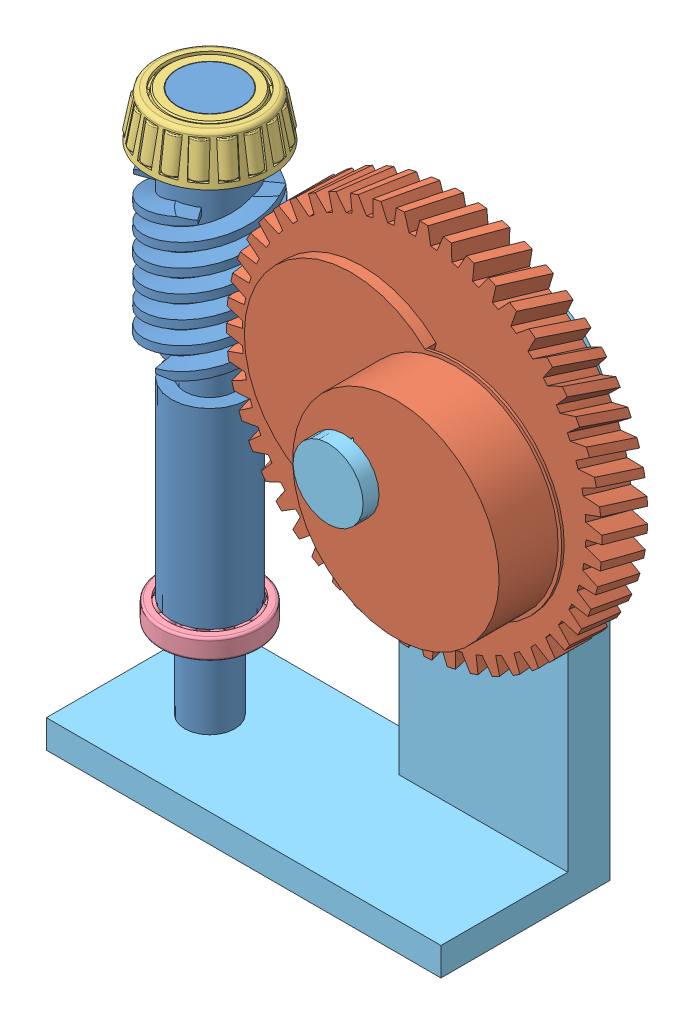
SolidWorks assembly gear Ass, configuration Default. Lengths in mm.
Overall size (190.62 222.52 70).
5 component instances, 5 part files, 9 mates.
Components (placement in the parent):
- worm gear-1: worm gear [Default] at (-73.4139 -3.3795 118.0562) x (0 0 1) z (-1 0 0) size (38.77 202.56 38.77)
- helical gear-1: helical gear [Default] at (8.555 135.9465 111.2804) x (0.238118 0.971236 0) z (0 0 1) size (133.38 133.38 45.09)
- Cone Bearing-1: Cone Bearing [Default] at (-73.4139 182.2945 118.0562) x (0 1 0) z (0 0 1) size (17.14 43.76 43.71)
- Ball Bearing-1: Ball Bearing [AFBMA 12.2 - 0.6250 - 1.3750 - 0.2812 - 10,DE,NC,10] at (-73.4139 36.2293 118.0562) x (0 1 0) z (0 0 1) size (7.14 34.92 34.92)
- Fixture-1: Fixture [Default] at (-73.4139 -5.9195 118.0562) x (0 0 -1) z (0 -1 0) size (70 140 171.77)
Mates (geometry in assembly coordinates):
- GearMate1: gear = 24.892 : 17.78 mm: cylinder of worm gear-1 through (-73.4139 -3.3795 118.0562) axis (0 -1 0) radius 8.89; cylinder of helical gear-1 through (8.555 135.9465 152.4284) axis (0 0 -1) radius 12.446
- Concentric1: concentric aligned: cylinder of worm gear-1 through (-73.4139 -3.3795 118.0562) axis (0 -1 0) radius 13.6525; cylinder of Cone Bearing-1 through (-73.4139 182.2945 118.0562) axis (0 -1 0) radius 11.1125
- Coincident1: coincident aligned: plane of worm gear-1 through (-73.4139 196.6455 129.1687) normal (0 1 0); plane of Cone Bearing-1 through (-91.036 196.6455 118.0562) normal (0 1 0)
- Concentric2: concentric anti-aligned: cylinder of worm gear-1 through (-73.4139 -3.3795 118.0562) axis (0 -1 0) radius 8.89; cylinder of Ball Bearing-1 through (-73.4139 15.5918 118.0562) axis (0 1 0) radius 7.9375
- Coincident2: coincident anti-aligned: plane of worm gear-1 through (-73.4139 39.8005 124.4062) normal (0 -1 0); plane of Ball Bearing-1 through (-82.1388 39.8005 118.0562) normal (0 1 0)
- InPlace1: in place: plane of worm gear-1 through (-73.4139 -5.9195 118.0562) normal (0 -1 0); plane of ? through (0 -5.9195 0) normal (0 -1 0); moOrthogonalPlaneRef_w of worm gear-1 through (-73.4139 -5.9195 118.0562) normal (0 -1 0); unknown of ?; plane of worm gear-1 through (-73.4139 -5.9195 118.0562) normal (0 -1 0); line of ? through (-55 0 -5.9195) axis (0 -1 0); plane of worm gear-1 through (-73.4139 -5.9195 118.0562) normal (0 -1 0); unknown of Fixture-1
- Coincident3: coincident aligned: plane of worm gear-1; plane of Fixture-1
- Coincident4: coincident aligned: moOrthogonalPlaneRef_w of worm gear-1 through (-73.4139 -5.9195 118.0562) normal (1 0 0); plane of Fixture-1
- Coincident5: coincident anti-aligned: moOrthogonalPlaneRef_w of worm gear-1 through (-73.4139 -5.9195 118.0562) normal (0 0 1); plane of Fixture-1
